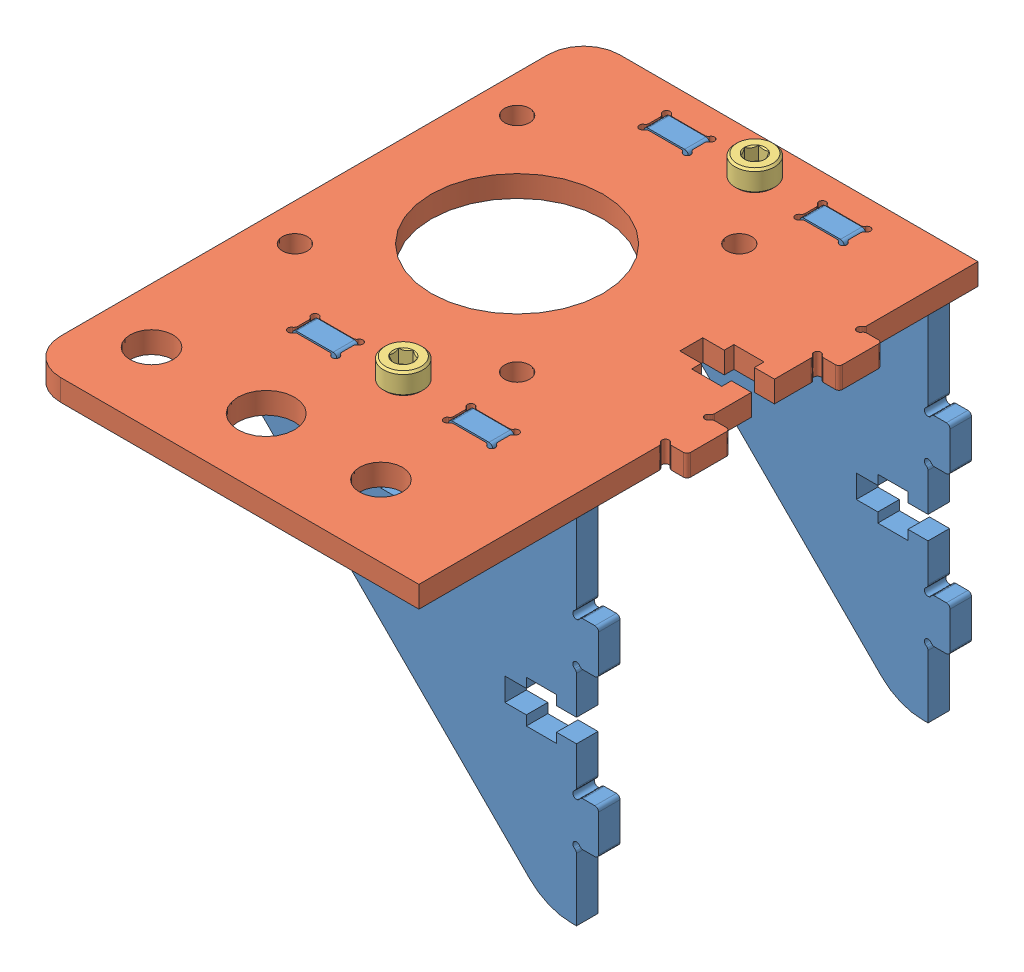
SolidWorks assembly Z-Motor-mount-right-side, configuration Default. Lengths in mm.
Overall size (58.08 55.4 78).
7 component instances, 4 part files, 16 mates.
Components (placement in the parent):
- Z-Motor-Mount-side-1: Z-Motor-Mount-side [Default] at (-30.5965 -617.8088 527.743) size (52.33 52.33 3)
- Z-Motor-Mount-top-v2-beta-1: Z-Motor-Mount-top-v2-beta [Default] at (1267.7712 441.3234 847.0964) x (0 0 -1) z (1 0 0) size (78 3 58)
- Z-Motor-Mount-side-2: Z-Motor-Mount-side [Default] at (-30.5965 -617.8088 478.703) size (52.33 52.33 3)
- 91292A114_TYPE 18-8 SS SOCKET HEAD CAP SCREW-2: 91292A114_TYPE 18-8 SS SOCKET HEAD CAP SCREW [91292A114] at (219.9216 432.3234 529.243) x (-0.552853 0 -0.833279) z (0 -1 0) size (5.5 5.5 15.58)
- 90576A102_ZINC-PLATED CLASS 8 STL NYLON-INSERT LOCKNUT-1: 90576A102_ZINC-PLATED CLASS 8 STL NYLON-INSERT LOCKNUT [90576A102] at (219.9216 438.5234 529.243) x (-1 0 0) z (0 0 -1) size (5.5 4.1 6.35)
- 90576A102_ZINC-PLATED CLASS 8 STL NYLON-INSERT LOCKNUT-2: 90576A102_ZINC-PLATED CLASS 8 STL NYLON-INSERT LOCKNUT [90576A102] at (219.9287 438.5234 480.203) x (0.5 0 -0.866025) z (-0.866025 0 -0.5) size (5.5 4.1 6.35)
- 91292A114_TYPE 18-8 SS SOCKET HEAD CAP SCREW-3: 91292A114_TYPE 18-8 SS SOCKET HEAD CAP SCREW [91292A114] at (219.9287 432.3234 480.203) x (0 0 1) z (0 -1 0) size (5.5 5.5 15.58)
Mates (geometry in assembly coordinates):
- Width1: width anti-aligned: plane of Z-Motor-Mount-side-1 through (245.5872 407.8729 527.743) normal (0 0 -1); plane of Z-Motor-Mount-side-1 through (245.5872 407.8729 530.743) normal (0 0 1); plane of Z-Motor-Mount-top-v2-beta-1 through (233.0455 444.3234 527.593) normal (0 0 1); plane of Z-Motor-Mount-top-v2-beta-1 through (228.5776 444.3234 530.893) normal (0 0 -1)
- Width2: width anti-aligned: plane of Z-Motor-Mount-side-1 through (233.8898 442.212 530.743) normal (1 0 0); plane of Z-Motor-Mount-side-1 through (227.7333 443.8887 530.743) normal (-1 0 0); plane of Z-Motor-Mount-top-v2-beta-1 through (233.9116 444.3234 530.0269) normal (-1 0 0); plane of Z-Motor-Mount-top-v2-beta-1 through (227.7116 444.3234 528.4591) normal (1 0 0)
- Coincident2: coincident anti-aligned: plane of Z-Motor-Mount-side-1 through (245.5872 441.3234 530.743) normal (0 1 0); plane of Z-Motor-Mount-top-v2-beta-1 through (195.5809 441.3234 547.723) normal (0 -1 0)
- Width4: width anti-aligned: plane of Z-Motor-Mount-side-2 through (227.7333 443.8887 481.703) normal (-1 0 0); plane of Z-Motor-Mount-side-2 through (233.8898 442.212 481.703) normal (1 0 0); plane of Z-Motor-Mount-top-v2-beta-1 through (227.7116 444.3234 479.4191) normal (1 0 0); plane of Z-Motor-Mount-top-v2-beta-1 through (233.9116 444.3234 480.9869) normal (-1 0 0)
- Concentric1: concentric anti-aligned: cylinder of Z-Motor-Mount-top-v2-beta-1 through (219.9287 444.3234 480.203) axis (0 -1 0) radius 1.6; circle of 90576A102_ZINC-PLATED CLASS 8 STL NYLON-INSERT LOCKNUT-2
- Parallel1: parallel anti-aligned: plane of Z-Motor-Mount-side-2 through (216.985 434.1408 481.703) normal (1 0 0); plane of 90576A102_ZINC-PLATED CLASS 8 STL NYLON-INSERT LOCKNUT-2 through (217.1787 434.5234 481.7907) normal (-1 0 0)
- Concentric2: concentric anti-aligned: cylinder of Z-Motor-Mount-top-v2-beta-1 through (219.9287 444.3234 480.203) axis (0 -1 0) radius 1.6; circle of 91292A114_TYPE 18-8 SS SOCKET HEAD CAP SCREW-3
- Coincident5: coincident anti-aligned: plane of Z-Motor-Mount-top-v2-beta-1 through (195.5809 444.3234 547.723) normal (0 1 0); plane of 91292A114_TYPE 18-8 SS SOCKET HEAD CAP SCREW-3 through (219.9287 444.3234 480.203) normal (0 -1 0)
- Coincident6: coincident aligned: plane of Z-Motor-Mount-side-1 through (216.985 438.5234 530.743) normal (0 -1 0); plane of 90576A102_ZINC-PLATED CLASS 8 STL NYLON-INSERT LOCKNUT-1 through (217.1716 438.5234 530.8307) normal (0 -1 0)
- Concentric3: concentric aligned: cylinder of Z-Motor-Mount-top-v2-beta-1 through (219.9216 444.3234 529.243) axis (0 -1 0) radius 1.6; circle of 90576A102_ZINC-PLATED CLASS 8 STL NYLON-INSERT LOCKNUT-1
- Parallel2: parallel aligned: plane of Z-Motor-Mount-side-1 through (222.885 438.5234 530.743) normal (-1 0 0); plane of 90576A102_ZINC-PLATED CLASS 8 STL NYLON-INSERT LOCKNUT-1 through (217.1716 442.5234 527.6553) normal (-1 0 0)
- Concentric4: concentric anti-aligned: cylinder of Z-Motor-Mount-top-v2-beta-1 through (219.9216 444.3234 529.243) axis (0 -1 0) radius 1.6; circle of 91292A114_TYPE 18-8 SS SOCKET HEAD CAP SCREW-2
- Coincident9: coincident anti-aligned: plane of Z-Motor-Mount-top-v2-beta-1 through (195.5809 444.3234 547.723) normal (0 1 0); plane of 91292A114_TYPE 18-8 SS SOCKET HEAD CAP SCREW-2 through (219.9216 444.3234 529.243) normal (0 -1 0)
- Coincident10: coincident anti-aligned: plane of Z-Motor-Mount-top-v2-beta-1 through (195.5809 441.3234 547.723) normal (0 -1 0); plane of Z-Motor-Mount-side-2 through (218.2933 441.3234 481.703) normal (0 1 0)
- Width5: width anti-aligned: plane of Z-Motor-Mount-side-2 through (245.5872 407.8729 478.703) normal (0 0 -1); plane of Z-Motor-Mount-side-2 through (245.5872 407.8729 481.703) normal (0 0 1); plane of Z-Motor-Mount-top-v2-beta-1 through (233.0455 444.3234 478.553) normal (0 0 1); plane of Z-Motor-Mount-top-v2-beta-1 through (228.5776 444.3234 481.853) normal (0 0 -1)
- Coincident14: coincident anti-aligned: plane of Z-Motor-Mount-side-2 through (216.985 438.5234 481.703) normal (0 -1 0); plane of 90576A102_ZINC-PLATED CLASS 8 STL NYLON-INSERT LOCKNUT-2 through (222.6787 438.5234 478.6153) normal (0 1 0)
